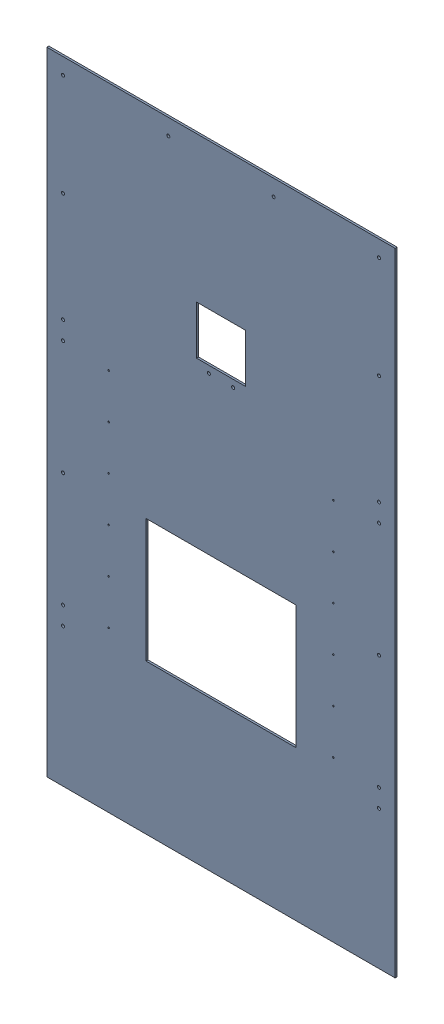
SolidWorks assembly GE-15034_ASM, configuration Default. Lengths in mm.
Overall size (1092.2 1981.2 22.23).
6 component instances, 4 part files, 0 mates.
Components (placement in the parent):
- GE-15003-1: GE-15003 [Default] at origin size (1092.2 1981.2 6.35)
- GE-15037-1: GE-15037 [Default] at (352.425 -139.7 -12.7) x (-1 0 0) z (0 0 1) size (63.5 838.2 9.53)
- GE-15037-2: GE-15037 [Default] at (-352.425 -139.7 -3.175) x (1 0 0) z (0 0 -1) size (63.5 838.2 9.53)
- GE-15036-1: GE-15036 [Default] at (-339.725 -139.7 -19.05) size (50.8 723.9 6.35)
- GE-15036-2: GE-15036 [Default] at (339.725 -139.7 -19.05) x (-1 0 0) z (0 0 1) size (50.8 723.9 6.35)
- GE-15035-1: GE-15035 [Default] at (0 73.025 -6.35) x (-1 0 0) z (0 0 -1) size (676.27 412.75 6.35)
